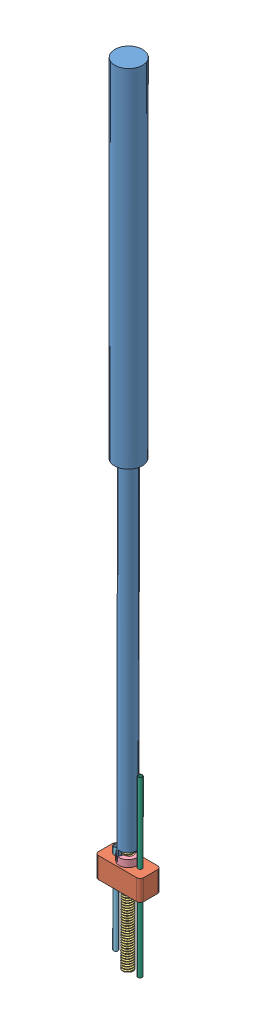
SolidWorks assembly TurnToolAndShuttle, configuration Default. Lengths in mm.
Overall size (6.73 114.03 6.62).
7 component instances, 6 part files, 5 mates.
Components (placement in the parent):
- TurnTool-1: TurnTool [Default] at (-5.4667 105.2012 -1.5) x (-0.910112 0.000938 -0.414361) z (-0.41436 0.000427 0.910113) size (5 100 5)
- ShuttleAssembly-1: ShuttleAssembly [Default] at (-3.017 -0.0275 4.0221) x (-0.999999 0.001031 0) z (0 0 -1) size (6.5 25.22 3.31)
  - drive_shuttle-1: drive_shuttle [Default] at (2.5582 1.9761 5.5221) size (6.5 3 3)
  - drive_threaded_rod_25mm-1: drive_threaded_rod_25mm [Default] at (2.5582 -8.5786 5.5221) x (0.813094 0 0.582132) z (-0.582132 0 0.813094) size (1.64 25.22 1.64)
  - Grooved Nut-1: Grooved Nut [Default] at (2.5582 1.9761 5.5221) x (0.414361 0 -0.910113) z (0.910113 0 0.414361) size (2.5 4 2.5)
  - guide_23g_13mm-1: guide_23g_13mm [Default] at (4.3082 -7.0239 5.5221) size (0.64 13 0.64)
  - stabilizer_23g_25mm-1: stabilizer_23g_25mm [Default] at (0.8082 -8.5786 5.5221) size (0.62 25 0.62)
Mates (geometry in assembly coordinates):
- Concentric1: concentric aligned: circle of TurnTool-1; circle of ShuttleAssembly-1/Grooved Nut-1
- Coincident2: coincident anti-aligned: plane of TurnTool-1 through (-5.5698 5.2013 -1.5) normal (-0.001031 -0.999999 0); plane of ShuttleAssembly-1/Grooved Nut-1 through (-5.1758 5.2009 -2.9688) normal (0.001031 0.999999 0)
- Concentric2: concentric aligned: circle of TurnTool-1; circle of ShuttleAssembly-1/Grooved Nut-1
- Width1: width anti-aligned: plane of ShuttleAssembly-1/Grooved Nut-1 through (-4.7207 5.2004 -2.7616) normal (-0.910112 0.000938 -0.414361); plane of ShuttleAssembly-1/Grooved Nut-1 through (-5.7973 5.2015 -1.6036) normal (0.910112 -0.000938 0.414361); plane of TurnTool-1 through (-5.1515 6.7009 -2.9584) normal (-0.910112 0.000938 -0.414361); plane of TurnTool-1 through (-4.7419 6.7004 -2.7719) normal (0.910112 -0.000938 0.414361)
- Coincident3: coincident aligned: plane of ShuttleAssembly-1/drive_shuttle-1 through (-2.32 4.948 0) normal (0 0 1); plane of assembly through (0 0 0) normal (0 0 1)
